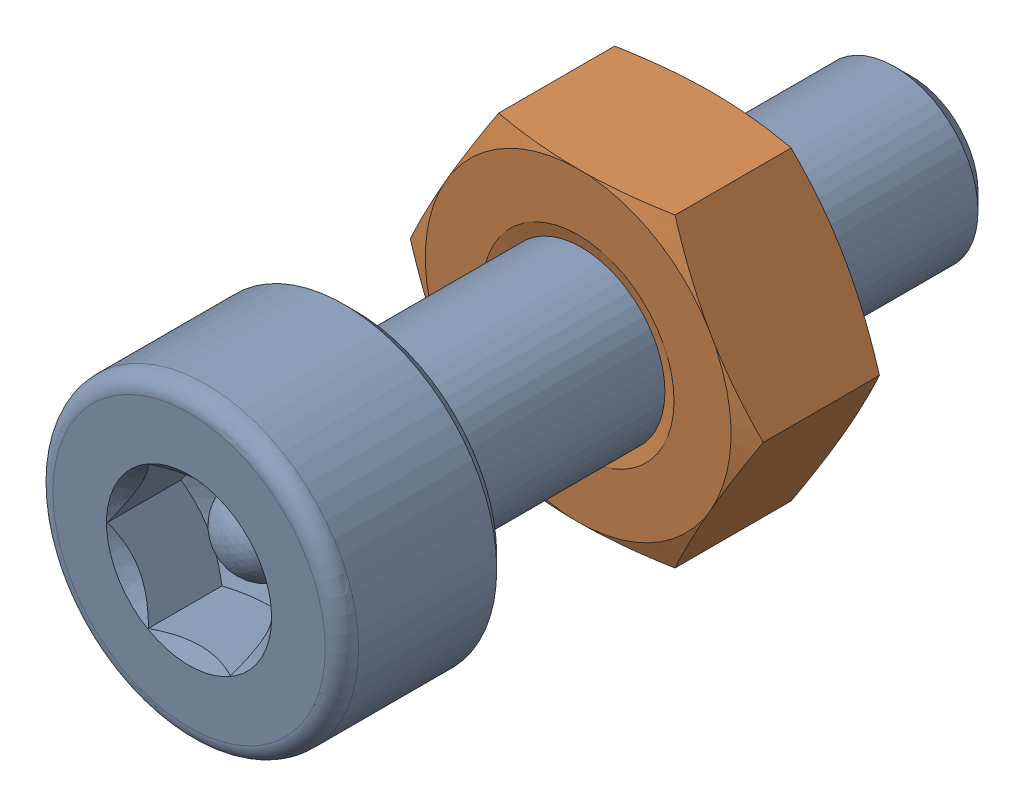
SolidWorks assembly Screw and Nut M3x010_022, configuration Varsayılan. Lengths in mm.
Overall size (6.35 5.5 13.14).
2 component instances, 2 part files, 0 mates.
Components (placement in the parent):
- M3x10-Screw021-1: M3x10-Screw021 [Varsayılan] at origin size (5.5 5.5 13.14)
- M3-Nut053-1: M3-Nut053 [Varsayılan] at (0 0 -4) x (-1 0 0) z (0 0 -1) size (6.35 5.5 2.4)
